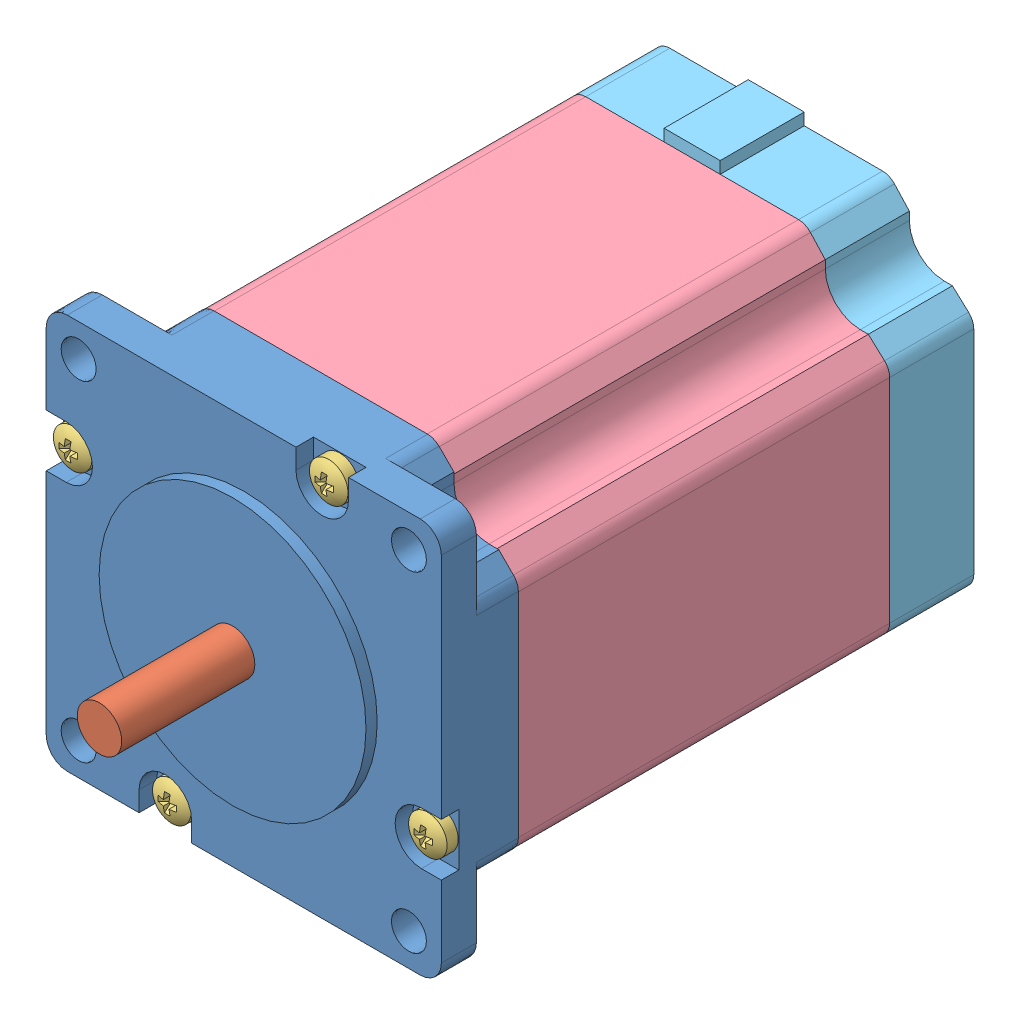
SolidWorks assembly ST5918L1008, configuration Standard. Lengths in mm.
Overall size (56.4 58.1 96.6).
9 component instances, 5 part files, 0 mates.
Components (placement in the parent):
- Frontcap_ST5918-1: Frontcap_ST5918 [Standard] at (0 0 -6.3) size (56.4 56.4 12.6)
- shaft_forward_5709-1: shaft_forward_5709 [Standard] at (0 0 25.3) x (1 0 0) z (0 0 -1) size (6.35 6.35 19)
- Schrauben_ISO_7045_M3-1: Schrauben_ISO_7045_M3 [Standard] at (-11.2 -25.35 2.2) x (0 1 0) z (1 0 0) size (5.57 2.46 5.76)
- Schrauben_ISO_7045_M3-2: Schrauben_ISO_7045_M3 [Standard] at (25.35 -11.2 2.2) x (1 0 0) z (0 -1 0) size (5.57 2.46 5.76)
- Schrauben_ISO_7045_M3-3: Schrauben_ISO_7045_M3 [Standard] at (11.2 25.35 2.2) x (1 0 0) z (0 -1 0) size (5.57 2.46 5.76)
- Schrauben_ISO_7045_M3-4: Schrauben_ISO_7045_M3 [Standard] at (-25.35 11.2 2.2) x (1 0 0) z (0 -1 0) size (5.57 2.46 5.76)
- Stator_5918_L-1: Stator_5918_L [Standard] at (0 0 -6.3) x (1 0 0) z (0 0 -1) size (56.4 56.4 53)
- Endcap ST5918_kompl-1: Endcap ST5918_kompl [Standard] at (0 0.85 -65.3) x (1 0 0) z (0 0 -1) size (56.4 58.1 12)
  - Endcap_5918-1: Endcap_5918 [Standard] at (0 0.85 -6) size (56.4 58.1 12)
